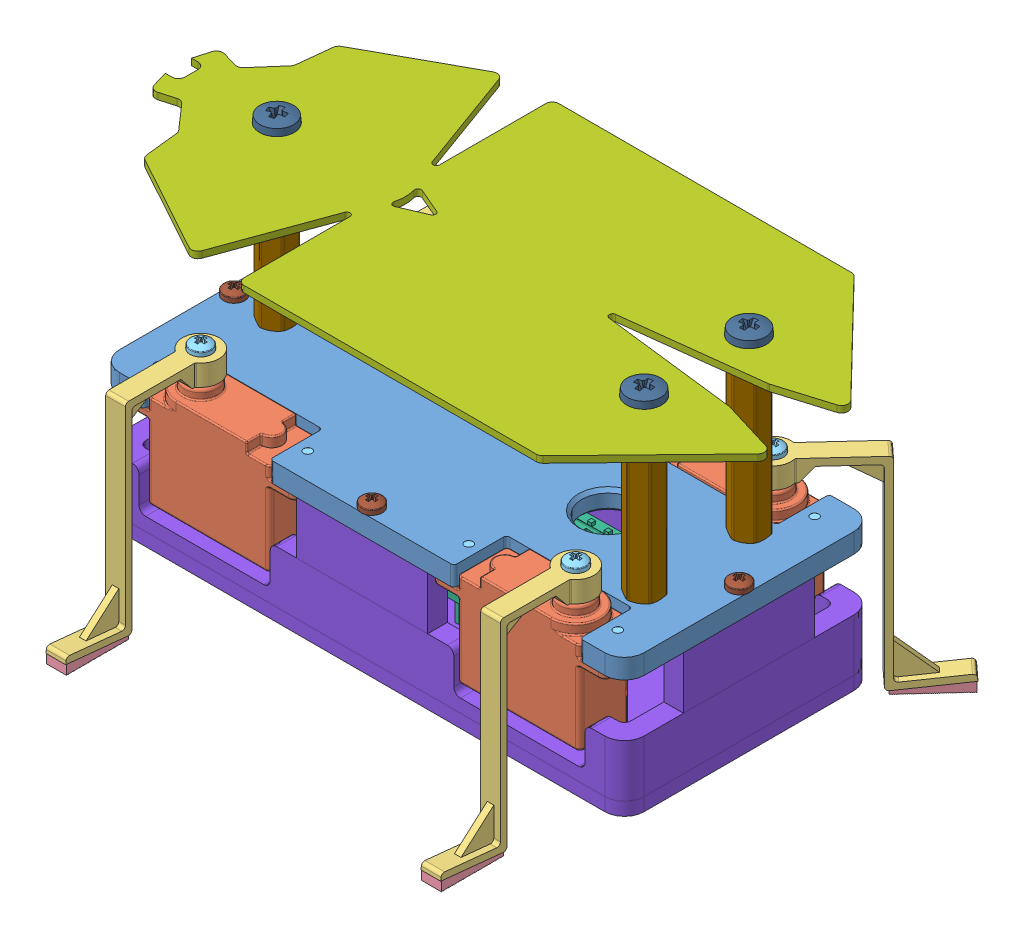
SolidWorks assembly InsectAssembly, configuration Default. Lengths in mm.
Overall size (95.71 53.52 74.2).
42 component instances, 11 part files, 84 mates.
Components (placement in the parent):
- BasePlate-1: BasePlate [Default] at origin size (80 3 38)
- Motor_Leg_Assembly-1: Motor_Leg_Assembly [Default] at (-33.0061 -12.3444 -11.19) x (1 0 0) z (0 -1 0) size (27.16 25.98 32.59) (flexible)
  - Hitec HS-35HD Ultra Nano Servo_NonTransparentCAD-1: Hitec HS-35HD Ultra Nano Servo_NonTransparentCAD [Default] x (1 0 0) z (0 0 -1) size (27.16 7.75 23.55)
  - Leg-1: Leg [Default] at (4.4196 -3.81 -20.7518) x (-1 0 0) z (0 1 0) size (5.59 30.95 24.89)
  - Grip-1: Grip [Default] at (4.4196 -16.31 10.2032) x (0 -1 0) z (1 0 0) size (9.5 1.45 3)
  - nylon_screw_M1x4x3.5-1: nylon_screw_M1x4x3.5 [M1.6 x 4 - Z --4N] at (4.4196 -3.81 -21.9248) x (0 0 1) z (-1 0 0) size (5.27 3.2 3.2)
- Motor_Leg_Assembly-2: Motor_Leg_Assembly [Default] at (33.0061 -12.3444 -18.81) x (-1 0 0) z (0 -1 0) size (35.87 22.11 32.59) (flexible)
  - Hitec HS-35HD Ultra Nano Servo_NonTransparentCAD-1: Hitec HS-35HD Ultra Nano Servo_NonTransparentCAD [Default] x (1 0 0) z (0 0 -1) size (27.16 7.75 23.55)
  - Leg-1: Leg [Default] at (4.4196 -3.81 -20.7518) x (0.736351 0.6766 0) z (0.6766 -0.736351 0) size (5.59 30.95 24.89)
  - Grip-1: Grip [Default] at (-4.0379 5.3944 10.2032) x (-0.6766 0.736351 0) z (-0.736351 -0.6766 0) size (9.5 1.45 3)
  - nylon_screw_M1x4x3.5-1: nylon_screw_M1x4x3.5 [M1.6 x 4 - Z --4N] at (4.4196 -3.81 -21.9248) x (0 0 1) z (-1 0 0) size (5.27 3.2 3.2)
- Motor_Leg_Assembly-3: Motor_Leg_Assembly [Default] at (-33.0061 -12.3444 18.81) x (1 0 0) z (0 -1 0) size (27.16 25.98 32.59) (flexible)
  - Hitec HS-35HD Ultra Nano Servo_NonTransparentCAD-1: Hitec HS-35HD Ultra Nano Servo_NonTransparentCAD [Default] x (1 0 0) z (0 0 -1) size (27.16 7.75 23.55)
  - Leg-1: Leg [Default] at (4.4196 -3.81 -20.7518) x (1 0 0) z (0 -1 0) size (5.59 30.95 24.89)
  - Grip-1: Grip [Default] at (4.4196 8.69 10.2032) x (0 1 0) z (-1 0 0) size (9.5 1.45 3)
  - nylon_screw_M1x4x3.5-1: nylon_screw_M1x4x3.5 [M1.6 x 4 - Z --4N] at (4.4196 -3.81 -21.9248) x (0 0 1) z (-1 0 0) size (5.27 3.2 3.2)
- Motor_Leg_Assembly-5: Motor_Leg_Assembly [Default] at (33.0061 -12.3444 11.19) x (-1 0 0) z (0 -1 0) size (27.16 25.98 32.59) (flexible)
  - Hitec HS-35HD Ultra Nano Servo_NonTransparentCAD-1: Hitec HS-35HD Ultra Nano Servo_NonTransparentCAD [Default] x (1 0 0) z (0 0 -1) size (27.16 7.75 23.55)
  - Leg-1: Leg [Default] at (4.4196 -3.81 -20.7518) x (-1 0 0) z (0 1 0) size (5.59 30.95 24.89)
  - Grip-1: Grip [Default] at (4.4196 -16.31 10.2032) x (0 -1 0) z (1 0 0) size (9.5 1.45 3)
  - nylon_screw_M1x4x3.5-1: nylon_screw_M1x4x3.5 [M1.6 x 4 - Z --4N] at (4.4196 -3.81 -21.9248) x (0 0 1) z (-1 0 0) size (5.27 3.2 3.2)
- Arduino NANO V3.0 ATMEGA328-2: Arduino NANO V3.0 ATMEGA328 [Default] at (-7.0797 -9.5 -0.0811) x (0.999912 0 -0.013301) z (0.013301 0 0.999912) size (45.1 13.95 17.78)
- CoverPlate-1: CoverPlate [Default] at (0 28 0) size (95.71 1 48)
- BaseCover-1: BaseCover [Default] at (0 -8 0) size (80 18 38)
- nylon_screw_M1x4x3.5-11: nylon_screw_M1x4x3.5 [M1.6 x 4 - Z --4N] at (-12.267 -2.316 -15) x (0 1 0) z (0 0 1) size (5.27 3.2 3.2)
- nylon_screw_M1x4x3.5-12: nylon_screw_M1x4x3.5 [M1.6 x 4 - Z --4N] at (-35 -2.316 -15) x (0 1 0) z (0 0 1) size (5.27 3.2 3.2)
- nylon_screw_M1x4x3.5-13: nylon_screw_M1x4x3.5 [M1.6 x 4 - Z --4N] at (12.267 -2.316 -15) x (0 1 0) z (0 0 1) size (5.27 3.2 3.2)
- nylon_screw_M1x4x3.5-10: nylon_screw_M1x4x3.5 [M1.6 x 4 - Z --4N] at (35 -2.316 -15) x (0 1 0) z (0 0 1) size (5.27 3.2 3.2)
- nylon_screw_M1x4x3.5-14: nylon_screw_M1x4x3.5 [M1.6 x 4 - Z --4N] at (35 -2.316 15) x (0 1 0) z (0 0 -1) size (5.27 3.2 3.2)
- nylon_screw_M1x4x3.5-15: nylon_screw_M1x4x3.5 [M1.6 x 4 - Z --4N] at (12.267 -2.316 15) x (0 1 0) z (0 0 -1) size (5.27 3.2 3.2)
- nylon_screw_M1x4x3.5-16: nylon_screw_M1x4x3.5 [M1.6 x 4 - Z --4N] at (-12.267 -2.316 15) x (0 1 0) z (0 0 -1) size (5.27 3.2 3.2)
- nylon_screw_M1x4x3.5-17: nylon_screw_M1x4x3.5 [M1.6 x 4 - Z --4N] at (-35 -2.316 15) x (0 1 0) z (0 0 -1) size (5.27 3.2 3.2)
- 93655A090_Male-Female Threaded Hex Standoff-1: 93655A090_Male-Female Threaded Hex Standoff [93655A090] at (-32 3 0) x (0.5 0 0.866025) z (0 1 0) size (4.5 5.08 29.09)
- 93655A090_Male-Female Threaded Hex Standoff-2: 93655A090_Male-Female Threaded Hex Standoff [93655A090] at (32 3 8) x (-0.5 0 -0.866025) z (0 1 0) size (4.5 5.08 29.09)
- 93655A090_Male-Female Threaded Hex Standoff-4: 93655A090_Male-Female Threaded Hex Standoff [93655A090] at (32 3 -8) x (-0.5 0 -0.866025) z (0 1 0) size (4.5 5.08 29.09)
- nylon_screw_M2.5x5-1: nylon_screw_M2.5x5 [M2.5 x 5 --5N] at (-32 30.5 0) x (0 -1 0) z (-0.960244 0 0.279164) size (6.47 5.3 5.3)
- nylon_screw_M2.5x5-2: nylon_screw_M2.5x5 [M2.5 x 5 --5N] at (32 30.5 -8) x (0 -1 0) z (-0.992877 0 0.119145) size (6.47 5.3 5.3)
- nylon_screw_M2.5x5-4: nylon_screw_M2.5x5 [M2.5 x 5 --5N] at (32 30.5 8) x (0 -1 0) z (-0.992877 0 0.119145) size (6.47 5.3 5.3)
- nylon_screw_M1x6x3.5-1: nylon_screw_M1x6x3.5 [M1.6 x 6 - Z -4N] at (0 4.3 17.5) x (0 -1 0) z (0 0 1) size (7.27 3.2 3.2)
- nylon_screw_M1x6x3.5-2: nylon_screw_M1x6x3.5 [M1.6 x 6 - Z -4N] at (38.5 4.3 0) x (0 -1 0) z (1 0 0) size (7.27 3.2 3.2)
- nylon_screw_M1x6x3.5-4: nylon_screw_M1x6x3.5 [M1.6 x 6 - Z -4N] at (0 4.3 -17.5) x (0 -1 0) z (0 0 -1) size (7.27 3.2 3.2)
- nylon_screw_M1x6x3.5-6: nylon_screw_M1x6x3.5 [M1.6 x 6 - Z -4N] at (-38.5 4.3 0) x (0 -1 0) z (-1 0 0) size (7.27 3.2 3.2)
Mates (geometry in assembly coordinates):
- Coincident7: coincident aligned: plane of BasePlate-1 through (0 0 0) normal (0 0 1)
- Coincident8: coincident aligned: plane of assembly through (0 0 0) normal (0 1 0); plane of BasePlate-1 through (0 0 0) normal (0 1 0)
- Coincident16: coincident anti-aligned: plane of BasePlate-1 through (0 0 0) normal (0 -1 0); plane of Motor_Leg_Assembly-1/Hitec HS-35HD Ultra Nano Servo_NonTransparentCAD-1 through (-14.2609 0 -18.81) normal (0 1 0)
- Concentric14: concentric aligned: cylinder of BasePlate-1 through (-35 3 -15) axis (0 1 0) radius 0.625; cylinder of Motor_Leg_Assembly-1/Hitec HS-35HD Ultra Nano Servo_NonTransparentCAD-1 through (-35 -12.3444 -15) axis (0 1 0) radius 0.9017
- Concentric15: concentric aligned: cylinder of BasePlate-1 through (-12.267 3 -15) axis (0 1 0) radius 0.625; cylinder of Motor_Leg_Assembly-1/Hitec HS-35HD Ultra Nano Servo_NonTransparentCAD-1 through (-12.267 -12.3444 -15) axis (0 1 0) radius 0.9017
- Parallel3: parallel: plane of BasePlate-1 through (-33.4663 3 -10.9825) normal (1 0 0); unknown of Motor_Leg_Assembly-1/Leg-1
- Concentric16: concentric aligned: cylinder of BasePlate-1 through (35 3 -15) axis (0 1 0) radius 0.625; cylinder of Motor_Leg_Assembly-2/Hitec HS-35HD Ultra Nano Servo_NonTransparentCAD-1 through (35 -12.3444 -15) axis (0 1 0) radius 0.9017
- Concentric17: concentric aligned: cylinder of BasePlate-1 through (12.267 3 -15) axis (0 1 0) radius 0.625; cylinder of Motor_Leg_Assembly-2/Hitec HS-35HD Ultra Nano Servo_NonTransparentCAD-1 through (12.267 -12.3444 -15) axis (0 1 0) radius 0.9017
- Coincident17: coincident anti-aligned: plane of BasePlate-1 through (0 0 0) normal (0 -1 0); plane of Motor_Leg_Assembly-2/Hitec HS-35HD Ultra Nano Servo_NonTransparentCAD-1 through (14.2609 0 -11.19) normal (0 1 0)
- Concentric18: concentric aligned: cylinder of BasePlate-1 through (-35 3 15) axis (0 1 0) radius 0.625; cylinder of Motor_Leg_Assembly-3/Hitec HS-35HD Ultra Nano Servo_NonTransparentCAD-1 through (-35 -12.3444 15) axis (0 1 0) radius 0.9017
- Concentric19: concentric aligned: cylinder of BasePlate-1 through (-12.267 3 15) axis (0 1 0) radius 0.625; cylinder of Motor_Leg_Assembly-3/Hitec HS-35HD Ultra Nano Servo_NonTransparentCAD-1 through (-12.267 -12.3444 15) axis (0 1 0) radius 0.9017
- Coincident20: coincident anti-aligned: plane of BasePlate-1 through (0 0 0) normal (0 -1 0); plane of Motor_Leg_Assembly-3/Hitec HS-35HD Ultra Nano Servo_NonTransparentCAD-1 through (-14.2609 0 11.19) normal (0 1 0)
- Coincident21: coincident anti-aligned: plane of BasePlate-1 through (0 0 0) normal (0 -1 0); plane of Motor_Leg_Assembly-5/Hitec HS-35HD Ultra Nano Servo_NonTransparentCAD-1 through (14.2609 0 18.81) normal (0 1 0)
- Concentric20: concentric aligned: cylinder of BasePlate-1 through (35 3 15) axis (0 1 0) radius 0.625; cylinder of Motor_Leg_Assembly-5/Hitec HS-35HD Ultra Nano Servo_NonTransparentCAD-1 through (35 -12.3444 15) axis (0 1 0) radius 0.9017
- Concentric21: concentric aligned: cylinder of BasePlate-1 through (12.267 3 15) axis (0 1 0) radius 0.625; cylinder of Motor_Leg_Assembly-5/Hitec HS-35HD Ultra Nano Servo_NonTransparentCAD-1 through (12.267 -12.3444 15) axis (0 1 0) radius 0.9017
- Coincident22: coincident aligned: plane of BasePlate-1 through (0 0 0) normal (1 0 0)
- Parallel4: parallel aligned: plane of BasePlate-1 through (-40 3 19) normal (-1 0 0); plane of Motor_Leg_Assembly-1/Leg-1 through (-30.0865 7.3152 -21.604) normal (-1 0 0)
- Parallel5: parallel anti-aligned: plane of Motor_Leg_Assembly-3/Leg-1 through (-27.0865 7.3152 21.604) normal (1 0 0); plane of BasePlate-1 through (-40 3 19) normal (-1 0 0)
- Parallel6: parallel aligned: plane of BasePlate-1 through (40 3 19) normal (1 0 0); plane of Motor_Leg_Assembly-5/Leg-1 through (30.0865 7.3152 21.604) normal (1 0 0)
- Parallel9: parallel aligned: plane of BasePlate-1 through (40 3 20) normal (1 0 0); unknown of Motor_Leg_Assembly-2/Leg-1
- Coincident46: coincident aligned: plane of BasePlate-1 through (0 0 0) normal (1 0 0); plane of CoverPlate-1 through (0 28 0) normal (1 0 0)
- Coincident47: coincident aligned: plane of BasePlate-1 through (0 0 0) normal (0 0 1); plane of CoverPlate-1 through (0 28 0) normal (0 0 1)
- Coincident48: coincident anti-aligned: plane of BasePlate-1 through (0 0 0) normal (0 -1 0); plane of BaseCover-1 through (0 0 0) normal (0 1 0)
- Coincident49: coincident aligned: plane of BasePlate-1 through (-40 3 19) normal (0 0 1); plane of BaseCover-1 through (0 0 19) normal (0 0 1)
- Coincident50: coincident aligned: plane of BasePlate-1 through (-40 3 19) normal (-1 0 0); plane of BaseCover-1 through (-40 -16 0) normal (-1 0 0)
- Concentric28: concentric anti-aligned: cylinder of Motor_Leg_Assembly-1/Hitec HS-35HD Ultra Nano Servo_NonTransparentCAD-1 through (-12.267 -12.3444 -15) axis (0 1 0) radius 0.9017; cylinder of cross recessed pan head screw_jis-7 through (-12.267 -27.716 -15) axis (0 -1 0) radius 1.6
- Coincident59: coincident anti-aligned: plane of Motor_Leg_Assembly-1/Hitec HS-35HD Ultra Nano Servo_NonTransparentCAD-1 through (-14.2609 -1.016 -18.81) normal (0 -1 0); plane of cross recessed pan head screw_jis-7 through (-13.067 -1.016 -15) normal (0 1 0)
- Parallel16: parallel aligned: plane of Motor_Leg_Assembly-1/Hitec HS-35HD Ultra Nano Servo_NonTransparentCAD-1 through (-33.0061 1.778 -18.81) normal (0 0 -1); plane of cross recessed pan head screw_jis-7 through (-11.467 -2.316 -14.76) normal (0 0 -1)
- Concentric29: concentric anti-aligned: cylinder of Motor_Leg_Assembly-1/Hitec HS-35HD Ultra Nano Servo_NonTransparentCAD-1 through (-35 -12.3444 -15) axis (0 1 0) radius 0.9017; cylinder of cross recessed pan head screw_jis-8 through (-35 -27.716 -15) axis (0 -1 0) radius 1.6
- Coincident61: coincident anti-aligned: plane of Motor_Leg_Assembly-1/Hitec HS-35HD Ultra Nano Servo_NonTransparentCAD-1 through (-33.0061 -1.016 -11.19) normal (0 -1 0); plane of cross recessed pan head screw_jis-8 through (-35.8 -1.016 -15) normal (0 1 0)
- Parallel17: parallel aligned: plane of Motor_Leg_Assembly-1/Hitec HS-35HD Ultra Nano Servo_NonTransparentCAD-1 through (-33.0061 1.778 -18.81) normal (0 0 -1); plane of cross recessed pan head screw_jis-8 through (-34.2 -2.316 -14.76) normal (0 0 -1)
- Concentric30: concentric anti-aligned: cylinder of Motor_Leg_Assembly-2/Hitec HS-35HD Ultra Nano Servo_NonTransparentCAD-1 through (12.267 -12.3444 -15) axis (0 1 0) radius 0.9017; cylinder of cross recessed pan head screw_jis-9 through (12.267 -27.716 -15) axis (0 -1 0) radius 1.6
- Coincident62: coincident anti-aligned: plane of Motor_Leg_Assembly-2/Hitec HS-35HD Ultra Nano Servo_NonTransparentCAD-1 through (14.2609 -1.016 -11.19) normal (0 -1 0); plane of cross recessed pan head screw_jis-9 through (11.467 -1.016 -15) normal (0 1 0)
- Parallel18: parallel aligned: plane of Motor_Leg_Assembly-2/Hitec HS-35HD Ultra Nano Servo_NonTransparentCAD-1 through (33.0061 1.778 -18.81) normal (0 0 -1); plane of cross recessed pan head screw_jis-9 through (13.067 -2.316 -14.76) normal (0 0 -1)
- Concentric31: concentric anti-aligned: cylinder of Motor_Leg_Assembly-2/Hitec HS-35HD Ultra Nano Servo_NonTransparentCAD-1 through (35 -12.3444 -15) axis (0 1 0) radius 0.9017; cylinder of cross recessed pan head screw_jis-10 through (35 -27.716 -15) axis (0 -1 0) radius 1.6
- Coincident63: coincident anti-aligned: plane of Motor_Leg_Assembly-2/Hitec HS-35HD Ultra Nano Servo_NonTransparentCAD-1 through (33.0061 -1.016 -18.81) normal (0 -1 0); plane of cross recessed pan head screw_jis-10 through (34.2 -1.016 -15) normal (0 1 0)
- Parallel19: parallel aligned: plane of Motor_Leg_Assembly-2/Hitec HS-35HD Ultra Nano Servo_NonTransparentCAD-1 through (33.0061 1.778 -18.81) normal (0 0 -1); plane of cross recessed pan head screw_jis-10 through (35.8 -2.316 -14.76) normal (0 0 -1)
- Concentric32: concentric anti-aligned: cylinder of Motor_Leg_Assembly-5/Hitec HS-35HD Ultra Nano Servo_NonTransparentCAD-1 through (35 -12.3444 15) axis (0 1 0) radius 0.9017; cylinder of cross recessed pan head screw_jis-11 through (35 -27.716 15) axis (0 -1 0) radius 1.6
- Coincident64: coincident anti-aligned: plane of Motor_Leg_Assembly-5/Hitec HS-35HD Ultra Nano Servo_NonTransparentCAD-1 through (33.0061 -1.016 11.19) normal (0 -1 0); plane of cross recessed pan head screw_jis-11 through (35.8 -1.016 15) normal (0 1 0)
- Parallel20: parallel aligned: plane of Motor_Leg_Assembly-5/Hitec HS-35HD Ultra Nano Servo_NonTransparentCAD-1 through (33.0061 1.778 18.81) normal (0 0 1); plane of cross recessed pan head screw_jis-11 through (34.2 -2.316 14.76) normal (0 0 1)
- Concentric33: concentric anti-aligned: cylinder of Motor_Leg_Assembly-5/Hitec HS-35HD Ultra Nano Servo_NonTransparentCAD-1 through (12.267 -12.3444 15) axis (0 1 0) radius 0.9017; cylinder of cross recessed pan head screw_jis-13 through (12.267 -27.716 15) axis (0 -1 0) radius 1.6
- Coincident65: coincident anti-aligned: plane of Motor_Leg_Assembly-5/Hitec HS-35HD Ultra Nano Servo_NonTransparentCAD-1 through (14.2609 -1.016 18.81) normal (0 -1 0); plane of cross recessed pan head screw_jis-13 through (13.067 -1.016 15) normal (0 1 0)
- Parallel21: parallel aligned: plane of Motor_Leg_Assembly-5/Hitec HS-35HD Ultra Nano Servo_NonTransparentCAD-1 through (33.0061 1.778 18.81) normal (0 0 1); plane of cross recessed pan head screw_jis-13 through (11.467 -2.316 14.76) normal (0 0 1)
- Concentric34: concentric anti-aligned: cylinder of Motor_Leg_Assembly-3/Hitec HS-35HD Ultra Nano Servo_NonTransparentCAD-1 through (-12.267 -12.3444 15) axis (0 1 0) radius 0.9017; cylinder of cross recessed pan head screw_jis-15 through (-12.267 -27.716 15) axis (0 -1 0) radius 1.6
- Coincident66: coincident anti-aligned: plane of Motor_Leg_Assembly-3/Hitec HS-35HD Ultra Nano Servo_NonTransparentCAD-1 through (-14.2609 -1.016 11.19) normal (0 -1 0); plane of cross recessed pan head screw_jis-15 through (-11.467 -1.016 15) normal (0 1 0)
- Parallel22: parallel aligned: plane of Motor_Leg_Assembly-3/Hitec HS-35HD Ultra Nano Servo_NonTransparentCAD-1 through (-33.0061 1.778 18.81) normal (0 0 1); plane of cross recessed pan head screw_jis-15 through (-13.067 -2.316 14.76) normal (0 0 1)
- Concentric35: concentric anti-aligned: cylinder of Motor_Leg_Assembly-3/Hitec HS-35HD Ultra Nano Servo_NonTransparentCAD-1 through (-35 -12.3444 15) axis (0 1 0) radius 0.9017; cylinder of cross recessed pan head screw_jis-17 through (-35 -27.716 15) axis (0 -1 0) radius 1.6
- Coincident67: coincident anti-aligned: plane of Motor_Leg_Assembly-3/Hitec HS-35HD Ultra Nano Servo_NonTransparentCAD-1 through (-33.0061 -1.016 18.81) normal (0 -1 0); plane of cross recessed pan head screw_jis-17 through (-34.2 -1.016 15) normal (0 1 0)
- Parallel23: parallel aligned: plane of Motor_Leg_Assembly-3/Hitec HS-35HD Ultra Nano Servo_NonTransparentCAD-1 through (-33.0061 1.778 18.81) normal (0 0 1); plane of cross recessed pan head screw_jis-17 through (-35.8 -2.316 14.76) normal (0 0 1)
- Parallel24: parallel aligned: plane of BasePlate-1 through (0 3 0) normal (0 1 0); plane of SAINSMART NANO V3.0 ATMEGA328-2 through (-7.0797 -8 -0.0811) normal (0 1 0)
- Concentric36: concentric anti-aligned: cone of BasePlate-1 through (-32 3 0) axis (0 1 0); cylinder of 93655A090_Male-Female Threaded Hex Standoff-1 through (-32 28 0) axis (0 -1 0) radius 785.3982
- Coincident69: coincident anti-aligned: plane of CoverPlate-1 through (0 28 0) normal (0 -1 0); plane of 93655A090_Male-Female Threaded Hex Standoff-1 through (-30.7226 28 -0.7375) normal (0 1 0)
- Coincident71: coincident anti-aligned: plane of BasePlate-1 through (0 3 0) normal (0 1 0); plane of 93655A090_Male-Female Threaded Hex Standoff-1 through (-30.9757 3 -0.5914) normal (0 -1 0)
- Parallel26: parallel aligned: plane of BasePlate-1 through (-40 3 19) normal (-1 0 0); plane of 93655A090_Male-Female Threaded Hex Standoff-1 through (-34.25 -3.8739 -1.299) normal (-1 0 0)
- Concentric37: concentric anti-aligned: cylinder of BasePlate-1 through (32 3 8) axis (0 1 0) radius 1.025; cylinder of 93655A090_Male-Female Threaded Hex Standoff-2 through (32 28 8) axis (0 -1 0) radius 785.3982
- Coincident73: coincident anti-aligned: plane of CoverPlate-1 through (0 28 0) normal (0 -1 0); plane of 93655A090_Male-Female Threaded Hex Standoff-2 through (30.7226 28 8.7375) normal (0 1 0)
- Coincident74: coincident anti-aligned: plane of BasePlate-1 through (0 3 0) normal (0 1 0); plane of 93655A090_Male-Female Threaded Hex Standoff-2 through (30.9757 3 8.5914) normal (0 -1 0)
- Parallel27: parallel aligned: plane of BasePlate-1 through (40 3 19) normal (1 0 0); plane of 93655A090_Male-Female Threaded Hex Standoff-2 through (34.25 -3.8739 9.299) normal (1 0 0)
- Concentric38: concentric anti-aligned: cylinder of BasePlate-1 through (32 3 -8) axis (0 1 0) radius 1.025; cylinder of 93655A090_Male-Female Threaded Hex Standoff-4 through (32 28 -8) axis (0 -1 0) radius 785.3982
- Coincident75: coincident anti-aligned: plane of CoverPlate-1 through (0 28 0) normal (0 -1 0); plane of 93655A090_Male-Female Threaded Hex Standoff-4 through (30.7226 28 -7.2625) normal (0 1 0)
- Coincident76: coincident anti-aligned: plane of BasePlate-1 through (0 3 0) normal (0 1 0); plane of 93655A090_Male-Female Threaded Hex Standoff-4 through (30.9757 3 -7.4086) normal (0 -1 0)
- Parallel28: parallel aligned: plane of BasePlate-1 through (40 3 19) normal (1 0 0); plane of 93655A090_Male-Female Threaded Hex Standoff-4 through (34.25 -3.8739 -6.701) normal (1 0 0)
- Distance1: distance = 8 mm anti-aligned: plane of SAINSMART NANO V3.0 ATMEGA328-2 through (-7.0797 -8 -0.0811) normal (0 1 0); plane of BasePlate-1 through (0 0 0) normal (0 -1 0)
- Concentric39: concentric aligned: cylinder of CoverPlate-1 through (-32 29 0) axis (0 1 0) radius 1.45; cylinder of cross recessed binding head screw_jis-1 through (-32 55.9 0) axis (0 1 0) radius 2.65
- Coincident77: coincident anti-aligned: plane of CoverPlate-1 through (0 29 0) normal (0 1 0); plane of cross recessed binding head screw_jis-1 through (-31.651 29 1.2003) normal (0 -1 0)
- Parallel29: parallel aligned: plane of CoverPlate-1 through (-2.1496 29 -7.3941) normal (0.279164 0 0.960244); plane of cross recessed binding head screw_jis-1 through (-31.5349 29.18 -0.5205) normal (0.279164 0 0.960244)
- Concentric40: concentric aligned: cylinder of CoverPlate-1 through (32 29 -8) axis (0 1 0) radius 1.45; cylinder of cross recessed binding head screw_jis-2 through (32 55.9 -8) axis (0 1 0) radius 2.65
- Coincident79: coincident anti-aligned: plane of CoverPlate-1 through (0 29 0) normal (0 1 0); plane of cross recessed binding head screw_jis-2 through (32.1489 29 -6.7589) normal (0 -1 0)
- Parallel30: parallel aligned: plane of CoverPlate-1 through (0.2129 29 1.7744) normal (0.119145 0 0.992877); plane of cross recessed binding head screw_jis-2 through (32.5436 29.18 -8.4379) normal (0.119145 0 0.992877)
- Concentric41: concentric aligned: cylinder of CoverPlate-1 through (32 29 8) axis (0 1 0) radius 1.45; cylinder of cross recessed binding head screw_jis-4 through (32 55.9 8) axis (0 1 0) radius 2.65
- Coincident80: coincident anti-aligned: plane of CoverPlate-1 through (0 29 0) normal (0 1 0); plane of cross recessed binding head screw_jis-4 through (32.1489 29 9.2411) normal (0 -1 0)
- Parallel31: parallel aligned: plane of CoverPlate-1 through (0.2129 29 1.7744) normal (0.119145 0 0.992877); plane of cross recessed binding head screw_jis-4 through (32.5436 29.18 7.5621) normal (0.119145 0 0.992877)
- Concentric42: concentric aligned: cylinder of BasePlate-1 through (0 3 17.5) axis (0 1 0) radius 0.9; cylinder of nylon_screw_M1x6x3.5-1 through (0 29.7 17.5) axis (0 1 0) radius 1.6
- Coincident81: coincident anti-aligned: plane of BasePlate-1 through (0 3 0) normal (0 1 0); plane of nylon_screw_M1x6x3.5-1 through (0.8 3 17.5) normal (0 -1 0)
- Parallel32: parallel anti-aligned: plane of BasePlate-1 through (-40 3 19) normal (0 0 1); plane of nylon_screw_M1x6x3.5-1 through (-0.8 4.3 17.74) normal (0 0 -1)
- Concentric43: concentric aligned: cylinder of BasePlate-1 through (38.5 3 0) axis (0 1 0) radius 0.9; cylinder of nylon_screw_M1x6x3.5-2 through (38.5 29.7 0) axis (0 1 0) radius 1.6
- Coincident83: coincident anti-aligned: plane of BasePlate-1 through (0 3 0) normal (0 1 0); plane of nylon_screw_M1x6x3.5-2 through (38.5 3 -0.8) normal (0 -1 0)
- Parallel33: parallel anti-aligned: plane of BasePlate-1 through (40 3 19) normal (1 0 0); plane of nylon_screw_M1x6x3.5-2 through (38.74 4.3 0.8) normal (-1 0 0)
- Concentric44: concentric aligned: cylinder of BasePlate-1 through (0 3 -17.5) axis (0 1 0) radius 0.9; cylinder of nylon_screw_M1x6x3.5-4 through (0 29.7 -17.5) axis (0 1 0) radius 1.6
- Coincident84: coincident anti-aligned: plane of BasePlate-1 through (0 3 0) normal (0 1 0); plane of nylon_screw_M1x6x3.5-4 through (-0.8 3 -17.5) normal (0 -1 0)
- Parallel34: parallel anti-aligned: plane of BasePlate-1 through (-40 3 -19) normal (0 0 -1); plane of nylon_screw_M1x6x3.5-4 through (0.8 4.3 -17.74) normal (0 0 1)
- Concentric45: concentric aligned: cylinder of BasePlate-1 through (-38.5 3 0) axis (0 1 0) radius 0.9; cylinder of nylon_screw_M1x6x3.5-6 through (-38.5 29.7 0) axis (0 1 0) radius 1.6
- Coincident85: coincident anti-aligned: plane of BasePlate-1 through (0 3 0) normal (0 1 0); plane of nylon_screw_M1x6x3.5-6 through (-38.5 3 0.8) normal (0 -1 0)
- Parallel35: parallel anti-aligned: plane of BasePlate-1 through (-40 3 19) normal (-1 0 0); plane of nylon_screw_M1x6x3.5-6 through (-38.74 4.3 -0.8) normal (1 0 0)
